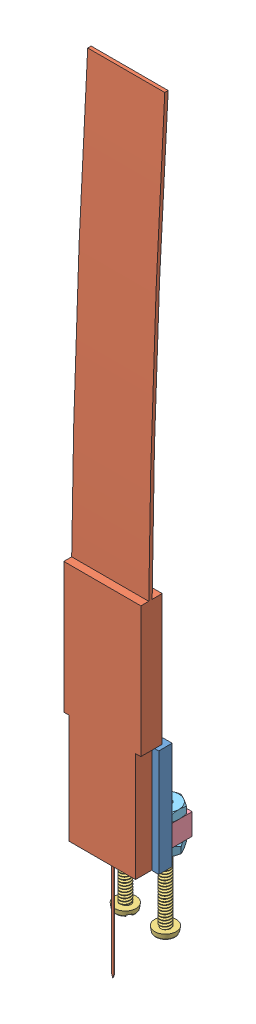
SolidWorks assembly holder_straight, configuration Default. Lengths in mm.
Overall size (7.5 72.83 5.88).
10 component instances, 5 part files, 11 mates.
Components (placement in the parent):
- npx_holder_shaft-1: npx_holder_shaft [Default] at origin size (7.5 10 1.25)
- Neuropixel 2019-1: Neuropixel 2019 [Default] at (-0.025 11.3 0.75) x (1 0 0) z (0 -1 0) size (7.2 2.55 72.83)
- 91800A062_METRIC CHEESE HEAD SLOTTED MACHINE SCREW-1: 91800A062_METRIC CHEESE HEAD SLOTTED MACHINE SCREW [91800A062] at (1.875 -11.3083 -1.25) x (0.87994 0 -0.475085) z (0 -1 0) size (2 2.04 11.07)
- nps_holder_screw_anchors-2: nps_holder_screw_anchors [pass-thru] at (1.875 -4.1 -1.25) size (2.5 2 2.5)
- 94150A112_316 STAINLESS STEEL HEX NUT-1: 94150A112_316 STAINLESS STEEL HEX NUT [94150A112] at (1.875 -1.7 -1.25) x (1 0 0) z (0 1 0) size (2.5 2.89 0.97)
- 94150A112_316 STAINLESS STEEL HEX NUT-2: 94150A112_316 STAINLESS STEEL HEX NUT [94150A112] at (1.875 -4.5 -1.25) x (0.855571 0 -0.517685) z (0 1 0) size (2.5 2.89 0.97)
- 94150A112_316 STAINLESS STEEL HEX NUT-3: 94150A112_316 STAINLESS STEEL HEX NUT [94150A112] at (-1.875 -1.7 -1.25) x (-1 0 0) z (0 1 0) size (2.5 2.89 0.97)
- nps_holder_screw_anchors-3: nps_holder_screw_anchors [pass-thru] at (-1.875 -4.1 -1.25) x (-1 0 0) z (0 0 -1) size (2.5 2 2.5)
- 94150A112_316 STAINLESS STEEL HEX NUT-4: 94150A112_316 STAINLESS STEEL HEX NUT [94150A112] at (-1.875 -4.5231 -1.25) x (-0.855571 0 -0.517685) z (0 -1 0) size (2.5 2.89 0.97)
- 91800A062_METRIC CHEESE HEAD SLOTTED MACHINE SCREW-2: 91800A062_METRIC CHEESE HEAD SLOTTED MACHINE SCREW [91800A062] at (-1.875 -11.3083 -1.25) x (-0.87994 0 -0.475085) z (0 -1 0) size (2 2.04 11.07)
Mates (geometry in assembly coordinates):
- Coincident3: coincident anti-aligned: plane of npx_holder_shaft-1 through (0 0 0) normal (0 0 -1); plane of nps_holder_screw_anchors-2 through (0.625 -2.1 0) normal (0 0 1)
- Distance1: distance = 0.9 mm aligned: plane of npx_holder_shaft-1 through (0 -5 0.75) normal (0 -1 0); plane of nps_holder_screw_anchors-2 through (1.875 -4.1 -1.25) normal (0 -1 0)
- Coincident5: coincident anti-aligned: plane of npx_holder_shaft-1 through (3.125 0 1.25) normal (-1 0 0); plane of nps_holder_screw_anchors-2 through (3.125 -2.1 -2.5) normal (1 0 0)
- Concentric1: concentric anti-aligned: circle of nps_holder_screw_anchors-2; circle of 91800A062_METRIC CHEESE HEAD SLOTTED MACHINE SCREW-1
- Concentric2: concentric anti-aligned: circle of 91800A062_METRIC CHEESE HEAD SLOTTED MACHINE SCREW-1; circle of 94150A112_316 STAINLESS STEEL HEX NUT-1
- Coincident6: coincident anti-aligned: plane of nps_holder_screw_anchors-2 through (1.875 -2.1 -1.25) normal (0 1 0); plane of 94150A112_316 STAINLESS STEEL HEX NUT-1 through (0.625 -2.1 -1.9717) normal (0 -1 0)
- Concentric3: concentric anti-aligned: circle of 91800A062_METRIC CHEESE HEAD SLOTTED MACHINE SCREW-1; circle of 94150A112_316 STAINLESS STEEL HEX NUT-2
- Coincident7: coincident anti-aligned: plane of nps_holder_screw_anchors-2 through (1.875 -4.1 -1.25) normal (0 -1 0); plane of 94150A112_316 STAINLESS STEEL HEX NUT-2 through (0.4319 -4.1 -1.2203) normal (0 1 0)
- Coincident8: coincident anti-aligned: plane of npx_holder_shaft-1 through (0 0 0.75) normal (0 0 1); plane of Neuropixel 2019-1 through (-0.025 11.3 0.75) normal (0 0 -1)
- Coincident9: coincident anti-aligned: plane of npx_holder_shaft-1 through (-3.125 0 1.25) normal (1 0 0); plane of Neuropixel 2019-1 through (-3.125 11.3 2.75) normal (-1 0 0)
- Coincident10: coincident aligned: plane of npx_holder_shaft-1 through (0 -5 0.75) normal (0 -1 0); plane of Neuropixel 2019-1 through (-0.025 -5 2.75) normal (0 -1 0)
